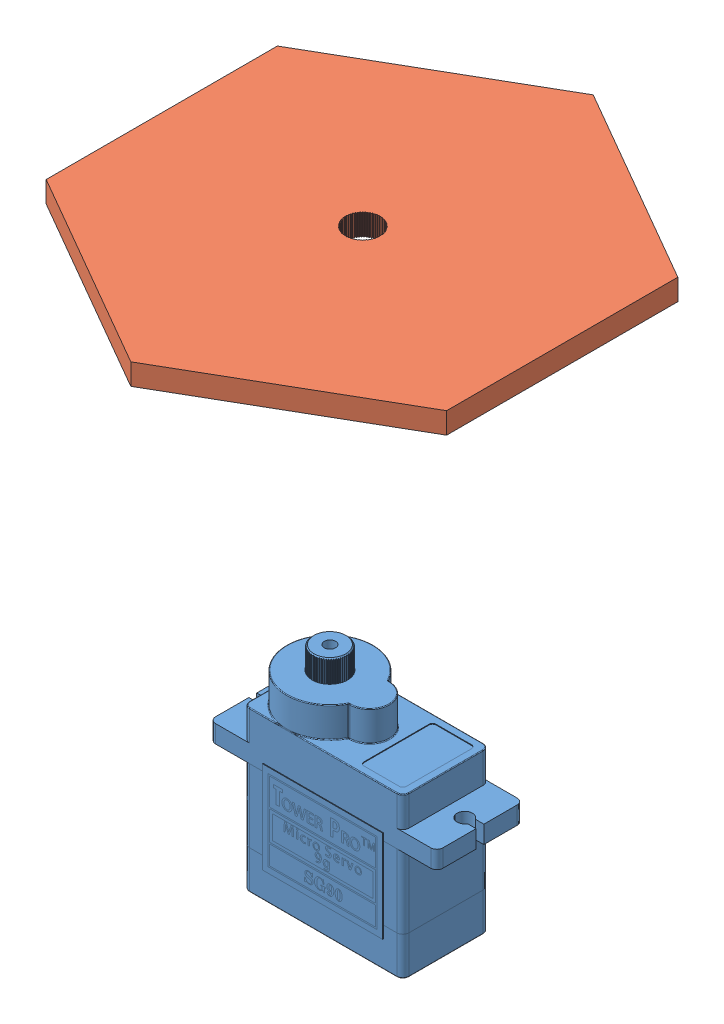
SolidWorks assembly arm connector test, configuration Default. Lengths in mm.
Overall size (76.02 52.08 69.93).
2 component instances, 2 part files, 0 mates.
Components (placement in the parent):
- SG90 - Micro Servo 9g - Tower Pro.1-1: SG90 - Micro Servo 9g - Tower Pro.1 [Peça] at (-19.3567 9.0187 1.1487) size (32.1 29.95 12.4)
- test arm-1: test arm [Default] at (-51.0373 47.4509 -29.9119) size (56.58 3 65.33)
